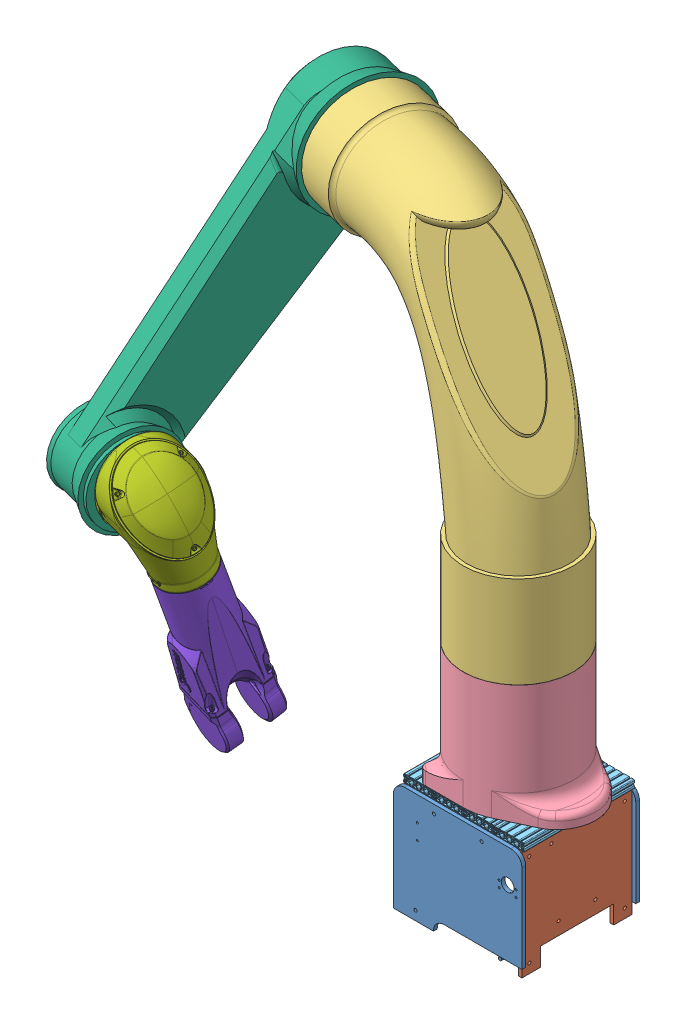
SolidWorks assembly robotaz, configuration Predeterminado. Lengths in mm.
Overall size (1108.5 1698.52 983.82).
13 component instances, 8 part files, 33 mates.
Components (placement in the parent):
- lateral eje y-2: lateral eje y [Predeterminado] at (310.1254 -91.7867 635) size (350 300 10)
- lateral eje y-3: lateral eje y [Predeterminado] at (310.1254 -91.7867 945) size (350 300 10)
- lateral eje x-1: lateral eje x [Predeterminado] at (290.1254 -91.7867 645) x (0 0 -1) z (1 0 0) size (300 300 10)
- lateral eje x-2: lateral eje x [Predeterminado] at (-9.8746 -91.7867 945) x (0 0 1) z (-1 0 0) size (300 300 10)
- Hombro-1: Hombro [Predeterminado] at (140.1254 800.2133 795) x (0.969972 0 0.243217) z (-0.243217 0 0.969972) size (711.98 977.51 300)
- BASE-1: BASE [Predeterminado] at (140.1254 230.2133 795) size (360.63 350 300)
- mesa-1: mesa [Default] at (19.168 219.1707 595) size (82 22 300)
- mesa-2: mesa [Default] at (101.168 219.1707 595) size (82 22 300)
- mesa-3: mesa [Default] at (183.168 219.1707 595) size (82 22 300)
- mesa-4: mesa [Default] at (265.168 218.1707 595) size (82 22 300)
- Brazo-1: Brazo [Predeterminado] at (-492.2726 1377.7192 636.4284) x (0.969972 0 0.243217) z (0.161159 0.74896 -0.642718) size (210 324.48 1084.48)
- Codo-1: Codo [Predeterminado] at (-417.5059 778.5511 1201.6784) x (-0.231587 -0.305534 0.923589) z (-0.969972 0 -0.243217) size (207.96 312 213.96)
- Antebrazo-1: Antebrazo [Predeterminado] at (-417.5811 779.5144 1201.9782) x (0.984403 0.02252 0.174481) z (0.074311 -0.952181 -0.296359) size (167.82 192.58 452.13)
Mates (geometry in assembly coordinates):
- Coincidente20: coincident aligned: plane of lateral eje y-2 through (-39.8746 -91.7867 645) normal (0 -1 0); plane of lateral eje x-1 through (300.1254 -91.7867 695) normal (0 -1 0)
- Coincidente30: coincident anti-aligned: plane of lateral eje y-3 through (310.1254 -91.7867 945) normal (0 0 -1); plane of lateral eje x-1 through (300.1254 -91.7867 945) normal (0 0 1)
- Coincidente31: coincident aligned: plane of lateral eje y-3 through (-39.8746 -91.7867 955) normal (0 -1 0); plane of lateral eje x-1 through (300.1254 -91.7867 945) normal (0 -1 0)
- Concéntrica23: concentric anti-aligned: circle of lateral eje x-1; circle of lateral eje x-2
- Concéntrica24: concentric anti-aligned: circle of lateral eje x-1; circle of lateral eje x-2
- Coincidente293: coincident anti-aligned: plane of lateral eje y-3 through (310.1254 -91.7867 945) normal (0 0 -1); plane of BASE-1 through (36.8698 265.2133 945) normal (0 0 1)
- Tangente1: tangent anti-aligned: plane of lateral eje x-2 through (-9.8746 -91.7867 945) normal (1 0 0); cylinder of BASE-1 through (140.1254 580.2133 795) axis (0 -1 0) radius 150
- Coincidente295: coincident anti-aligned: plane of Hombro-1 through (140.1254 580.2133 795) normal (0 -1 0); plane of BASE-1 through (140.1254 580.2133 795) normal (0 1 0)
- Coincidente296: coincident anti-aligned: circle of Hombro-1; circle of BASE-1
- Coincidente299: coincident anti-aligned: plane of lateral eje y-2 through (310.1254 -91.7867 645) normal (0 0 1); plane of lateral eje x-2 through (-19.8746 -91.7867 645) normal (0 0 -1)
- Coincidente300: coincident anti-aligned: plane of lateral eje y-3 through (310.1254 -91.7867 945) normal (0 0 -1); plane of lateral eje x-1 through (300.1254 -91.7867 945) normal (0 0 1)
- Tangente2: tangent anti-aligned: plane of lateral eje x-1 through (290.1254 -91.7867 645) normal (-1 0 0); cylinder of BASE-1 through (140.1254 580.2133 795) axis (0 -1 0) radius 150
- Coincidente302: coincident aligned: plane of lateral eje y-2 through (-39.8746 -91.7867 645) normal (-1 0 0); plane of lateral eje y-3 through (-39.8746 -91.7867 955) normal (-1 0 0)
- Coincidente303: coincident aligned: line of lateral eje x-2 through (-19.8746 208.2133 945) axis (0 0 -1); line of mesa-1 through (-19.8746 208.2133 945) axis (0 0 -1)
- Coincidente304: coincident anti-aligned: plane of lateral eje x-2 through (-19.8746 208.2133 645) normal (0 1 0); plane of mesa-1 through (52.5254 208.2133 945) normal (0 -1 0)
- Coincidente306: coincident aligned: line of lateral eje x-2 through (-19.8746 208.2133 945) axis (0 0 -1); line of mesa-1 through (-19.8746 208.2133 945) axis (0 0 -1)
- Coincidente307: coincident anti-aligned: line of lateral eje y-3 through (280.1254 208.2133 945) axis (-1 0 0); line of mesa-1 through (-19.8746 208.2133 945) axis (1 0 0)
- Coincidente308: coincident anti-aligned: plane of mesa-1 through (60.1254 210.2133 945) normal (1 0 0); plane of mesa-2 through (60.1254 215.8133 945) normal (-1 0 0)
- Coincidente310: coincident anti-aligned: plane of mesa-2 through (142.1254 210.2133 945) normal (1 0 0); plane of mesa-3 through (142.1254 215.8133 945) normal (-1 0 0)
- Coincidente312: coincident anti-aligned: plane of mesa-3 through (224.1254 210.2133 945) normal (1 0 0); plane of mesa-4 through (224.1254 214.8133 945) normal (-1 0 0)
- Coincidente314: coincident anti-aligned: line of lateral eje y-3 through (280.1254 208.2133 945) axis (-1 0 0); line of mesa-4 through (226.1254 208.2133 945) axis (1 0 0)
- Coincidente316: coincident anti-aligned: line of lateral eje y-3 through (280.1254 208.2133 945) axis (-1 0 0); line of mesa-2 through (62.1254 208.2133 945) axis (1 0 0)
- Coincidente317: coincident anti-aligned: line of lateral eje y-3 through (280.1254 208.2133 945) axis (-1 0 0); line of mesa-3 through (144.1254 208.2133 945) axis (1 0 0)
- Coincidente318: coincident anti-aligned: plane of BASE-1 through (140.1254 230.2133 795) normal (0 -1 0); plane of mesa-2 through (107.7254 230.2133 945) normal (0 1 0)
- Coincidente322: coincident anti-aligned: plane of Hombro-1 through (-375.876 1377.7192 665.6145) normal (-0.969972 0 -0.243217); plane of Brazo-1 through (-375.876 1377.7192 665.6145) normal (0.969972 0 0.243217)
- Concéntrica25: concentric anti-aligned: circle of Hombro-1; circle of Brazo-1
- Coincidente323: coincident anti-aligned: plane of Brazo-1 through (-524.2028 778.5511 1174.9245) normal (0.969972 0 0.243217); plane of Codo-1 through (-524.2028 778.5511 1174.9245) normal (-0.969972 0 -0.243217)
- Concéntrica26: concentric anti-aligned: circle of Brazo-1; circle of Codo-1
- Coincidente324: coincident anti-aligned: plane of Codo-1 through (-405.9134 630.0108 1155.4464) normal (0.074311 -0.952181 -0.296359); plane of Antebrazo-1 through (-405.9134 630.0108 1155.4464) normal (-0.074311 0.952181 0.296359)
- Concéntrica27: concentric aligned: cylinder of Codo-1 through (-405.9134 630.0108 1155.4464) axis (-0.074311 0.952181 0.296359) radius 69.5; circle of Antebrazo-1
- Coincidente329: coincident anti-aligned: line of lateral eje y-2 through (-9.8746 208.2133 635) axis (0 0 1); line of lateral eje x-2 through (-9.8746 208.2133 945) axis (0 0 -1)
- Paralelo3: parallel anti-aligned: plane of lateral eje y-2 through (-39.8746 208.2133 645) normal (0 1 0); plane of mesa-4 through (298.5254 207.2133 945) normal (0 -1 0)
- Coincidente334: coincident anti-aligned: plane of lateral eje y-2 through (-39.8746 208.2133 645) normal (0 1 0); plane of mesa-3 through (216.5254 208.2133 945) normal (0 -1 0)
